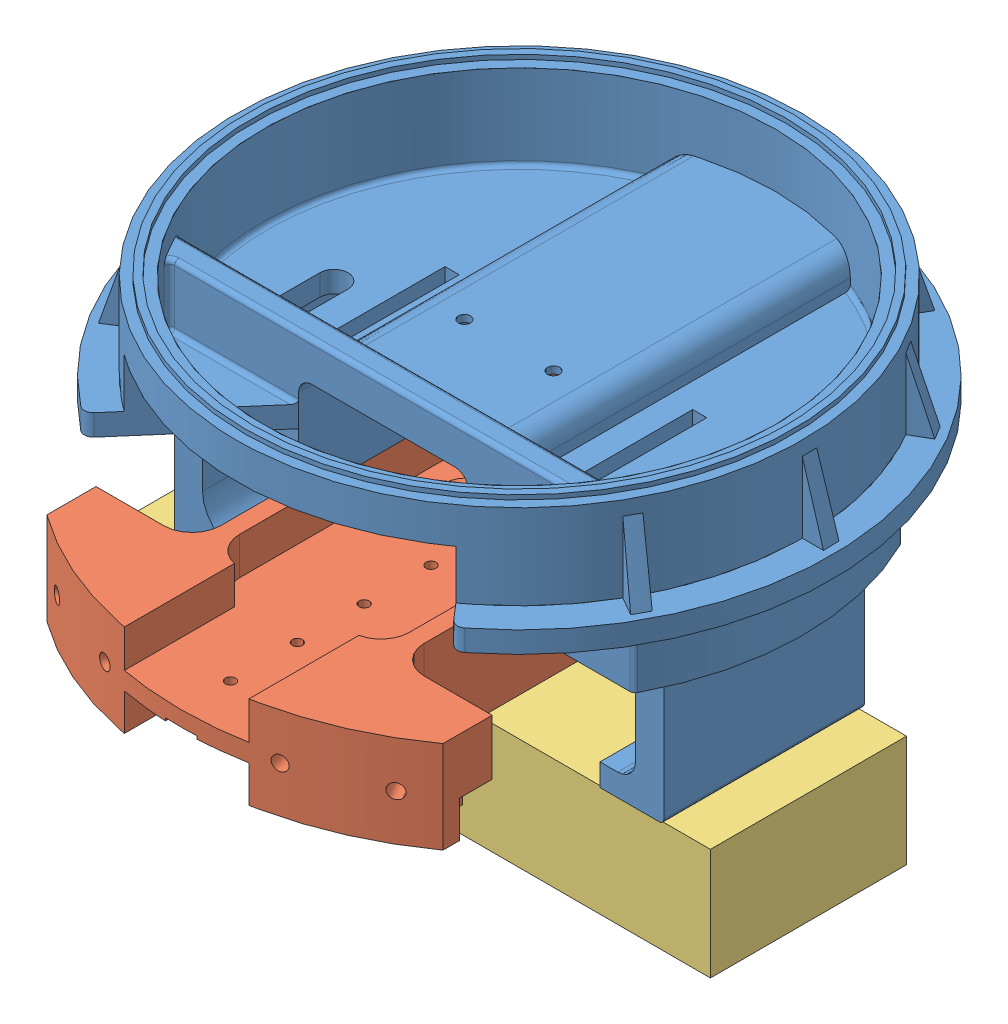
SolidWorks assembly ensr cap assembly, configuration Default. Lengths in mm.
Overall size (140.24 93.71 151.89).
3 component instances, 3 part files, 7 mates.
Components (placement in the parent):
- eNSR_cap.2 with vesc mounting-1: eNSR_cap.2 with vesc mounting [Default] at (27.314 78.095 125.6452) size (140.24 68.71 130.29)
- Baseplate_v5-1: Baseplate_v5 [Default] at (27.314 54.2952 125.6452) x (0 0 1) z (0 -1 0) size (151.89 88.9 20.7)
- controller-1: controller [Default] at (1.3035 9.2012 125.6452) size (130 25 44)
Mates (geometry in assembly coordinates):
- Coincident1: coincident anti-aligned: plane of eNSR_cap.2 with vesc mounting-1 through (27.314 78.095 125.6452) normal (1 0 0); plane of Baseplate_v5-1
- Concentric1: concentric anti-aligned: cylinder of eNSR_cap.2 with vesc mounting-1 through (27.314 101.9075 125.6452) axis (0 -1 0) radius 63.5; cylinder of Baseplate_v5-1 through (27.314 51.7552 125.6452) axis (0 1 0) radius 75.946
- Coincident2: coincident anti-aligned: plane of eNSR_cap.2 with vesc mounting-1 through (27.314 64.2012 125.6452) normal (0 -1 0); plane of Baseplate_v5-1 through (14.614 64.2012 169.3743) normal (0 1 0)
- Coincident5: coincident anti-aligned: plane of eNSR_cap.2 with vesc mounting-1 through (27.314 34.2012 125.6452) normal (0 -1 0); plane of controller-1 through (1.3035 34.2012 125.6452) normal (0 1 0)
- Parallel1: parallel aligned: line of eNSR_cap.2 with vesc mounting-1 through (92.314 39.2012 147.6452) axis (0 0 -1); line of controller-1 through (92.314 34.2012 147.761) axis (0 0 -1)
- Coincident9: coincident anti-aligned: plane of eNSR_cap.2 with vesc mounting-1 through (27.314 34.2012 125.6452) normal (0 -1 0); plane of controller-1 through (1.3035 34.2012 125.6452) normal (0 1 0)
- Coincident11: coincident aligned: plane of eNSR_cap.2 with vesc mounting-1 through (27.314 78.095 125.6452) normal (0 0 1); plane of controller-1 through (1.3035 9.2012 125.6452) normal (0 0 1)
